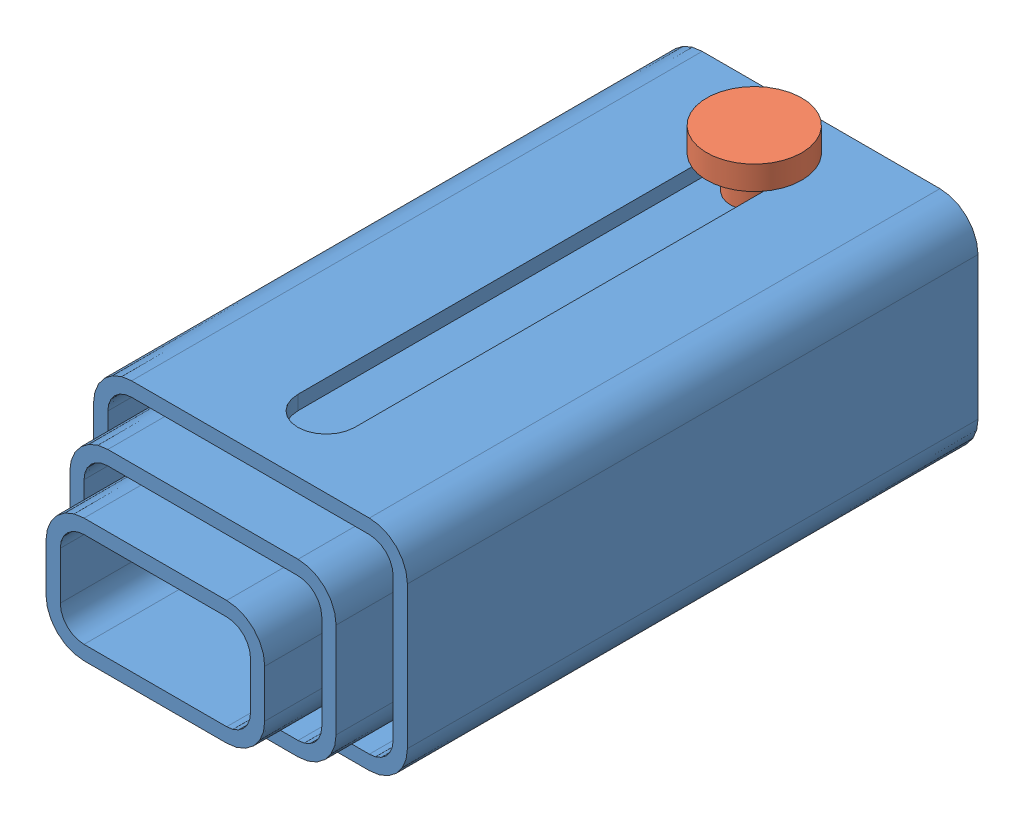
SolidWorks assembly advancedmechanicalmates, configuration Default. Lengths in mm.
Overall size (66 60 140).
4 component instances, 2 part files, 10 mates.
Components (placement in the parent):
- advancedmechanicalmates-1: advancedmechanicalmates [Large] at (-9.156 76.245 111.3234) size (66 46 120)
- advancedmechanicalmates-2: advancedmechanicalmates [Medium] at (-14.156 81.245 121.3234) size (56 36 120)
- advancedmechanicalmates-3: advancedmechanicalmates [Small] at (-19.156 86.245 131.3234) size (46 26 120)
- pin-1: pin [Default] at (-9.156 77.1933 66.3234) x (0.215494 0 -0.976505) z (0 1 0) size (20 20 60)
Mates (geometry in assembly coordinates):
- Width1: width anti-aligned: plane of advancedmechanicalmates-1 through (-35.1043 97.1933 171.3234) normal (0 -1 0); plane of advancedmechanicalmates-1 through (-35.1043 57.1933 171.3234) normal (0 1 0); plane of advancedmechanicalmates-2 through (-30.1043 62.1933 181.3234) normal (0 1 0); plane of advancedmechanicalmates-2 through (-30.1043 92.1933 181.3234) normal (0 -1 0)
- Width2: width aligned: plane of advancedmechanicalmates-1 through (-40.1043 92.1933 171.3234) normal (1 0 0); plane of advancedmechanicalmates-1 through (19.8957 92.1933 171.3234) normal (-1 0 0); plane of advancedmechanicalmates-2 through (17.8957 87.1933 181.3234) normal (1 0 0); plane of advancedmechanicalmates-2 through (-38.1043 87.1933 181.3234) normal (-1 0 0)
- Width3: width anti-aligned: plane of advancedmechanicalmates-2 through (-30.1043 92.1933 181.3234) normal (0 -1 0); plane of advancedmechanicalmates-2 through (-30.1043 62.1933 181.3234) normal (0 1 0); plane of advancedmechanicalmates-3 through (-25.1043 90.1933 191.3234) normal (0 1 0); plane of advancedmechanicalmates-3 through (-25.1043 64.1933 191.3234) normal (0 -1 0)
- Width4: width anti-aligned: plane of advancedmechanicalmates-2 through (-35.1043 87.1933 181.3234) normal (1 0 0); plane of advancedmechanicalmates-2 through (14.8957 87.1933 181.3234) normal (-1 0 0); plane of advancedmechanicalmates-3 through (-33.1043 82.1933 191.3234) normal (-1 0 0); plane of advancedmechanicalmates-3 through (12.8957 82.1933 191.3234) normal (1 0 0)
- Coincident1: coincident aligned: plane of advancedmechanicalmates-3 through (4.8957 72.1933 171.3234) normal (0 0 1); plane of advancedmechanicalmates-2 through (9.8957 67.1933 171.3234) normal (0 0 1)
- Coincident3: coincident aligned: plane of advancedmechanicalmates-1 through (14.8957 62.1933 171.3234) normal (0 0 1); plane of advancedmechanicalmates-2 through (9.8957 67.1933 171.3234) normal (0 0 1)
- Linear/Linear Coupler1: linear coupler = 1 : 2 mm: plane of advancedmechanicalmates-2 through (9.8957 67.1933 181.3234) normal (0 0 1); plane of advancedmechanicalmates-3 through (4.8957 72.1933 191.3234) normal (0 0 1)
- Slot2: slot anti-aligned: cylinder of pin-1 through (-9.156 102.1933 66.3234) axis (0 -1 0) radius 5; plane of advancedmechanicalmates-1 through (-15.156 54.1933 66.3234) normal (1 0 0); cylinder of advancedmechanicalmates-1 through (-9.156 54.1933 66.3234) axis (0 1 0) radius 6
- Width6: width aligned: plane of pin-1 through (-9.156 102.1933 66.3234) normal (0 -1 0); plane of pin-1 through (-9.156 52.1933 66.3234) normal (0 1 0); plane of advancedmechanicalmates-1 through (-35.1043 54.1933 171.3234) normal (0 -1 0); plane of advancedmechanicalmates-1 through (-35.1043 100.1933 171.3234) normal (0 1 0)
- Tangent2: tangent aligned: plane of advancedmechanicalmates-2 through (9.8957 67.1933 61.3234) normal (0 0 -1); cylinder of pin-1 through (-9.156 102.1933 66.3234) axis (0 -1 0) radius 5
